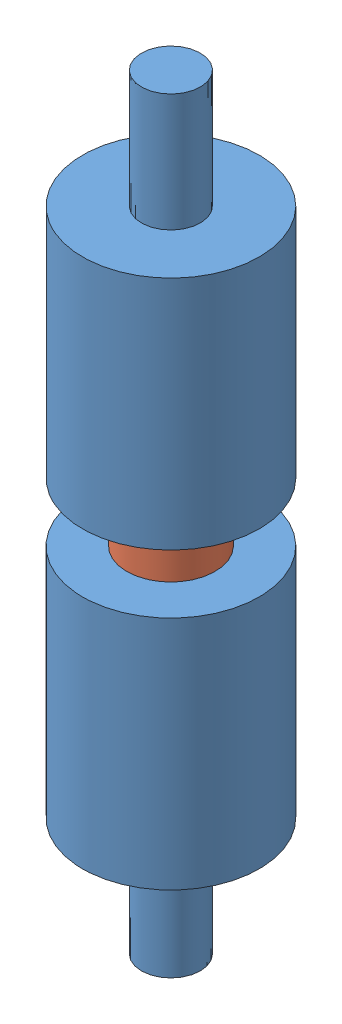
SolidWorks assembly Assem1, configuration Default. Lengths in mm.
Overall size (20.26 65 20.26).
3 component instances, 2 part files, 4 mates.
Components (placement in the parent):
- DifferentialRod_Exterior-1: DifferentialRod_Exterior [Default] at (-31.4322 5.3649 2.7507) size (15 30 15)
- DifferentialRod_Exterior-2: DifferentialRod_Exterior [Default] at (-31.4322 70.3649 2.7507) x (-0.885259 0 -0.465098) z (-0.465098 0 0.885259) size (15 30 15)
- DifferentialRod_Interior-1: DifferentialRod_Interior [Default] at (-31.4322 23.8649 2.7507) x (-0.227951 0 0.973673) z (-0.973673 0 -0.227951) size (7.5 28 7.5)
Mates (geometry in assembly coordinates):
- Concentric1: concentric anti-aligned: cylinder of DifferentialRod_Exterior-1 through (-31.4322 21.3649 2.7507) axis (0 1 0) radius 3.75; cylinder of DifferentialRod_Interior-1 through (-31.4322 51.8649 2.7507) axis (0 -1 0) radius 3.75
- Concentric2: concentric aligned: cylinder of DifferentialRod_Exterior-2 through (-31.4322 65.9147 2.7507) axis (0 -1 0) radius 3.75; cylinder of DifferentialRod_Interior-1 through (-31.4322 51.8649 2.7507) axis (0 -1 0) radius 3.75
- Distance1: distance = 2.5 mm anti-aligned: plane of DifferentialRod_Exterior-1 through (-31.4322 21.3649 2.7507) normal (0 1 0); plane of DifferentialRod_Interior-1 through (-31.4322 23.8649 2.7507) normal (0 -1 0)
- Distance2: distance = 5 mm anti-aligned: plane of DifferentialRod_Exterior-2 through (-31.4322 40.3649 2.7507) normal (0 -1 0); plane of DifferentialRod_Exterior-1 through (-31.4322 35.3649 2.7507) normal (0 1 0)
